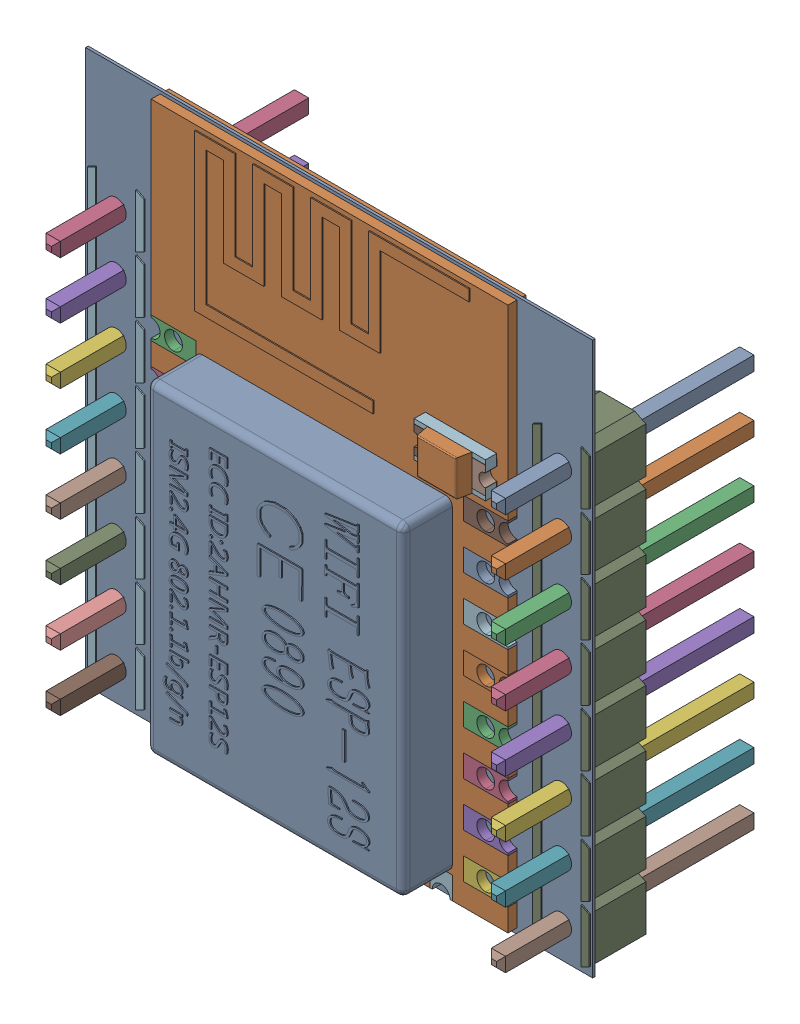
SolidWorks assembly PCB-1, configuration 默认. Lengths in mm.
Overall size (22.73 24.76 11.54).
50 component instances, 25 part files, 0 mates.
Components (placement in the parent):
- Board-1-1: Board-1 [默认] at origin size (22.73 24.76 0.12)
  - Open CASCADE STEP translator 6.8 1.1.1-1: Open CASCADE STEP translator 6.8 1.1.1 [默认] at (0 0 -0.1168) size (22.73 24.76 0.12)
- P3-1: P3 [默认] at origin size (16 24.38 3.05)
  - 0411-2-1: 0411-2 [默认] at (11.34 12.4403 0) x (0 1 0) z (-1 0 0) size (24.38 3.05 16)
    - User_Library-ESP8266-12E_PCB1-1: User_Library-ESP8266-12E_PCB1 [默认] x (-1 0 0) z (0 0 1) size (24.38 0.8 16)
    - User_Library-ESP8266-12E_Pin1-1: User_Library-ESP8266-12E_Pin1 [默认] at (3.31 0 8) x (-1 0 0) z (0 -1 0) size (1 2 0.8)
    - User_Library-ESP8266-12E_Pin1-2: User_Library-ESP8266-12E_Pin1 [默认] at (1.31 0 8) x (-1 0 0) z (0 -1 0) size (1 2 0.8)
    - User_Library-ESP8266-12E_Pin1-3: User_Library-ESP8266-12E_Pin1 [默认] at (-0.69 0 8) x (-1 0 0) z (0 -1 0) size (1 2 0.8)
    - User_Library-ESP8266-12E_Pin1-4: User_Library-ESP8266-12E_Pin1 [默认] at (-2.69 0 8) x (-1 0 0) z (0 -1 0) size (1 2 0.8)
    - User_Library-ESP8266-12E_Pin1-5: User_Library-ESP8266-12E_Pin1 [默认] at (-4.69 0 8) x (-1 0 0) z (0 -1 0) size (1 2 0.8)
    - User_Library-ESP8266-12E_Pin1-6: User_Library-ESP8266-12E_Pin1 [默认] at (-6.69 0 8) x (-1 0 0) z (0 -1 0) size (1 2 0.8)
    - User_Library-ESP8266-12E_Pin1-7: User_Library-ESP8266-12E_Pin1 [默认] at (-8.69 0 8) x (-1 0 0) z (0 -1 0) size (1 2 0.8)
    - User_Library-ESP8266-12E_Pin1-8: User_Library-ESP8266-12E_Pin1 [默认] at (-10.69 0 8) x (-1 0 0) z (0 -1 0) size (1 2 0.8)
    - User_Library-ESP8266-12E_Pin1-9: User_Library-ESP8266-12E_Pin1 [默认] at (3.31 0 -8) x (1 0 0) z (0 -1 0) size (1 2 0.8)
    - User_Library-ESP8266-12E_Pin1-10: User_Library-ESP8266-12E_Pin1 [默认] at (-0.69 0 -8) x (1 0 0) z (0 -1 0) size (1 2 0.8)
    - User_Library-ESP8266-12E_Pin1-11: User_Library-ESP8266-12E_Pin1 [默认] at (1.31 0 -8) x (1 0 0) z (0 -1 0) size (1 2 0.8)
    - User_Library-ESP8266-12E_Pin1-12: User_Library-ESP8266-12E_Pin1 [默认] at (-2.69 0 -8) x (1 0 0) z (0 -1 0) size (1 2 0.8)
    - User_Library-ESP8266-12E_Pin1-13: User_Library-ESP8266-12E_Pin1 [默认] at (-4.69 0 -8) x (1 0 0) z (0 -1 0) size (1 2 0.8)
    - User_Library-ESP8266-12E_Pin1-14: User_Library-ESP8266-12E_Pin1 [默认] at (-6.69 0 -8) x (1 0 0) z (0 -1 0) size (1 2 0.8)
    - User_Library-ESP8266-12E_Pin1-15: User_Library-ESP8266-12E_Pin1 [默认] at (-8.69 0 -8) x (1 0 0) z (0 -1 0) size (1 2 0.8)
    - User_Library-ESP8266-12E_Pin1-16: User_Library-ESP8266-12E_Pin1 [默认] at (-10.69 0 -8) x (1 0 0) z (0 -1 0) size (1 2 0.8)
    - User_Library-ESP8266-12E_Pin2-1: User_Library-ESP8266-12E_Pin2 [默认] at (-12.19 0 5) x (0 0 1) z (0 1 0) size (1 1 0.8)
    - User_Library-ESP8266-12E_Pin2-2: User_Library-ESP8266-12E_Pin2 [默认] at (-12.19 0 3) x (0 0 -1) z (0 -1 0) size (1 1 0.8)
    - User_Library-ESP8266-12E_Pin2-3: User_Library-ESP8266-12E_Pin2 [默认] at (-12.19 0 1) x (0 0 1) z (0 1 0) size (1 1 0.8)
    - User_Library-ESP8266-12E_Pin2-4: User_Library-ESP8266-12E_Pin2 [默认] at (-12.19 0 -1) x (0 0 1) z (0 1 0) size (1 1 0.8)
    - User_Library-ESP8266-12E_Pin2-5: User_Library-ESP8266-12E_Pin2 [默认] at (-12.19 0 -3) x (0 0 1) z (0 1 0) size (1 1 0.8)
    - User_Library-ESP8266-12E_Pin2-6: User_Library-ESP8266-12E_Pin2 [默认] at (-12.19 0 -5) x (0 0 1) z (0 1 0) size (1 1 0.8)
    - User_Library-ESP8266-12E_Lid-1: User_Library-ESP8266-12E_Lid [默认] at (-3.84 -1.5 0.25) x (0 0 -1) z (0 -1 0) size (11.5 14.5 2.25)
    - User_Library-ESP8266-12E_Antenne-1: User_Library-ESP8266-12E_Antenne [默认] at (4.99 -0.425 6) x (0 0 -1) z (0 -1 0) size (12.3 7 0.05)
    - User_Library-ESP8266-12E_Surface_Mount_Chip_LED_3.2x1.6mm-1: User_Library-ESP8266-12E_Surface_Mount_Chip_LED_3.2x1.6mm [默认] at (6.19 -0.41 -7.5) x (0 0 1) z (0 -1 0) size (3.2 1.6 1.13)
- Open CASCADE STEP translator 6.8 1.3-1: Open CASCADE STEP translator 6.8 1.3 [默认] at origin size (2.54 20.32 11.54)
  - Header8_2.54mm-1: Header8_2.54mm [默认] at (1.3969 10.3123 -1.2168) x (0 -1 0) z (1 0 0) size (0.64 11.54 0.64)
  - Header8_2.54mm-2-1: Header8_2.54mm-2 [默认] at (1.3969 10.3123 -1.2168) x (0 -1 0) z (1 0 0) size (0.64 11.54 0.64)
  - Header8_2.54mm-3-1: Header8_2.54mm-3 [默认] at (1.3969 10.3123 -1.2168) x (0 -1 0) z (1 0 0) size (0.64 11.54 0.64)
  - Header8_2.54mm-4-1: Header8_2.54mm-4 [默认] at (1.3969 10.3123 -1.2168) x (0 -1 0) z (1 0 0) size (0.64 11.54 0.64)
  - Header8_2.54mm-5-1: Header8_2.54mm-5 [默认] at (1.3969 10.3123 -1.2168) x (0 -1 0) z (1 0 0) size (0.64 11.54 0.64)
  - Header8_2.54mm-6-1: Header8_2.54mm-6 [默认] at (1.3969 10.3123 -1.2168) x (0 -1 0) z (1 0 0) size (0.64 11.54 0.64)
  - Header8_2.54mm-7-1: Header8_2.54mm-7 [默认] at (1.3969 10.3123 -1.2168) x (0 -1 0) z (1 0 0) size (0.64 11.54 0.64)
  - Header8_2.54mm-8-1: Header8_2.54mm-8 [默认] at (1.3969 10.3123 -1.2168) x (0 -1 0) z (1 0 0) size (0.64 11.54 0.64)
  - Header8_2.54mm-9-1: Header8_2.54mm-9 [默认] at (1.3969 10.3123 -1.2168) x (0 -1 0) z (1 0 0) size (20.32 2.54 2.54)
- 1-10-1: 1-10 [默认] at origin size (2.54 20.32 11.54)
  - Header8_2.54mm_RGB255-1: Header8_2.54mm_RGB255 [默认] at (21.3613 10.3123 -1.2168) x (0 -1 0) z (1 0 0) size (0.64 11.54 0.64)
  - Header8_2.54mm_RGB255-11-1: Header8_2.54mm_RGB255-11 [默认] at (21.3613 10.3123 -1.2168) x (0 -1 0) z (1 0 0) size (0.64 11.54 0.64)
  - Header8_2.54mm_RGB255-12-1: Header8_2.54mm_RGB255-12 [默认] at (21.3613 10.3123 -1.2168) x (0 -1 0) z (1 0 0) size (0.64 11.54 0.64)
  - Header8_2.54mm_RGB255-13-1: Header8_2.54mm_RGB255-13 [默认] at (21.3613 10.3123 -1.2168) x (0 -1 0) z (1 0 0) size (0.64 11.54 0.64)
  - Header8_2.54mm_RGB255-14-1: Header8_2.54mm_RGB255-14 [默认] at (21.3613 10.3123 -1.2168) x (0 -1 0) z (1 0 0) size (0.64 11.54 0.64)
  - Header8_2.54mm_RGB255-15-1: Header8_2.54mm_RGB255-15 [默认] at (21.3613 10.3123 -1.2168) x (0 -1 0) z (1 0 0) size (0.64 11.54 0.64)
  - Header8_2.54mm_RGB255-16-1: Header8_2.54mm_RGB255-16 [默认] at (21.3613 10.3123 -1.2168) x (0 -1 0) z (1 0 0) size (0.64 11.54 0.64)
  - Header8_2.54mm_RGB255-17-1: Header8_2.54mm_RGB255-17 [默认] at (21.3613 10.3123 -1.2168) x (0 -1 0) z (1 0 0) size (0.64 11.54 0.64)
  - Header8_2.54mm_RGB255-18-1: Header8_2.54mm_RGB255-18 [默认] at (21.3613 10.3123 -1.2168) x (0 -1 0) z (1 0 0) size (20.32 2.54 2.54)
